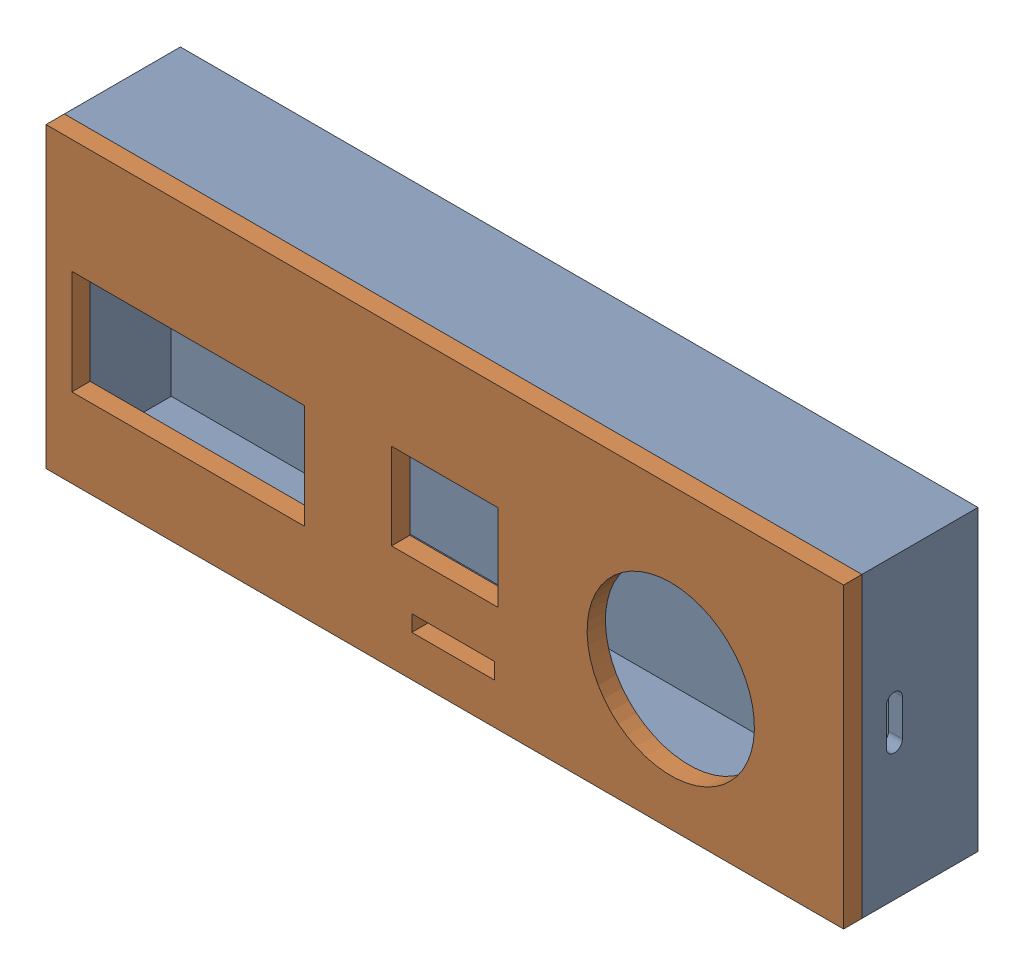
SolidWorks assembly IoT Case Assembled, configuration Default. Lengths in mm.
Overall size (174 65 29.32).
2 component instances, 2 part files, 1 mates.
Components (placement in the parent):
- IoT case-1: IoT case [Default] at (-453.8078 -18.4311 237.99) size (174 65 28)
- lid-1: lid [Default] at (-453.8078 -18.4311 267.314) x (1 0 0) z (0 1 0) size (174 7.5 65)
Mates (geometry in assembly coordinates):
- Concentric1: concentric anti-aligned: circle of IoT case-1; circle of lid-1
